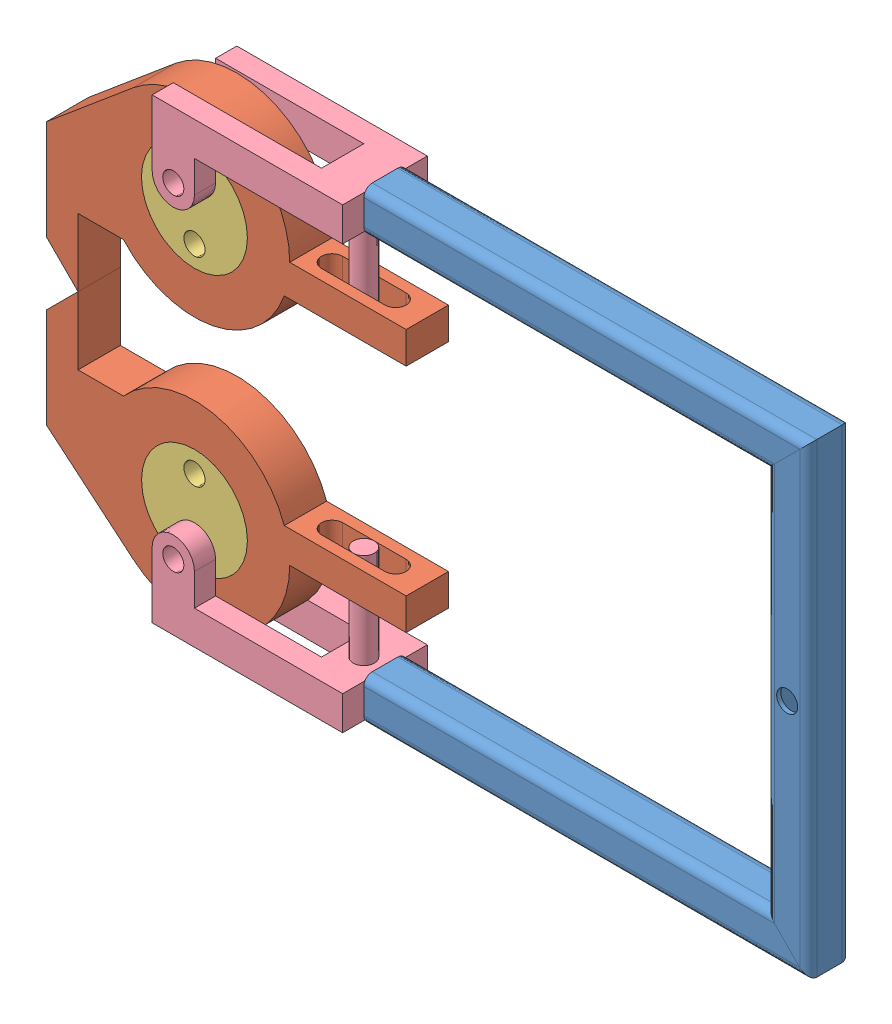
SolidWorks assembly Assem1, configuration Default. Lengths in mm.
Overall size (360 220 40).
7 component instances, 4 part files, 18 mates.
Components (placement in the parent):
- Part1-1: Part1 [Default<As Machined>] at (95.7224 77.7115 186.8939) size (210 220 20)
- Part2-1: Part2 [Default] at (15.7224 115.7115 176.8939) size (170 107 20)
- Part3-1: Part3 [Default] at (15.7224 115.7115 176.8939) x (-1 0 0) z (0 0 1) size (50 50 20)
- Part3-2: Part3 [Default] at (15.7224 239.7115 176.8939) x (1 0 0) z (0 0 1) size (50 50 20)
- Part4-1: Part4 [Default] at (5.7224 69.7115 206.8939) size (120 61 40)
- Part4-2: Part4 [Default] at (5.7224 285.7115 166.8939) x (1 0 0) z (0 0 -1) size (120 61 40)
- Part2-3: Part2 [Default] at (15.7224 239.7115 196.8939) x (1 0 0) z (0 0 -1) size (170 107 20)
Mates (geometry in assembly coordinates):
- Coincident1: coincident: plane of Part1-1 through (295.7224 83.7115 194.8939) normal (0 0 -1); plane of Part4-1 through (95.7224 85.7115 194.8939) normal (0 0 1)
- Coincident2: coincident: plane of Part1-1 through (295.7224 85.7115 192.8939) normal (0 -1 0); plane of Part4-1 through (5.7224 85.7115 206.8939) normal (0 1 0)
- Coincident3: coincident: plane of Part1-1 through (95.7224 269.7115 192.8939) normal (0 1 0); plane of Part4-2 through (5.7224 269.7115 166.8939) normal (0 -1 0)
- Coincident4: coincident: plane of Part1-1 through (95.7224 271.7115 194.8939) normal (0 0 -1); plane of Part4-2 through (95.7224 269.7115 194.8939) normal (0 0 1)
- Concentric1: concentric: cylinder of Part2-1 through (15.7224 115.7115 196.8939) axis (0 0 -1) radius 25; cylinder of Part3-1 through (15.7224 115.7115 196.8939) axis (0 0 -1) radius 25; cylinder of Part3-1 through (15.7224 115.7115 196.8939) axis (0 0 -1) radius 25
- Coincident6: coincident: plane of Part2-1 through (15.7224 115.7115 196.8939) normal (0 0 1); plane of Part3-1 through (15.7224 115.7115 196.8939) normal (0 0 1)
- Concentric3: concentric: cylinder of Part3-2 through (15.7224 254.7115 196.8939) axis (0 0 -1) radius 5; cylinder of Part4-2 through (15.7224 254.7115 206.8939) axis (0 0 -1) radius 5
- Concentric4: concentric: cylinder of Part3-1 through (15.7224 100.7115 196.8939) axis (0 0 -1) radius 5; cylinder of Part4-1 through (15.7224 100.7115 196.8939) axis (0 0 1) radius 5
- Coincident7: coincident: plane of Part3-2 through (15.6758 239.7116 196.8939) normal (0 0 1); plane of Part2-3 through (15.6758 239.7116 196.8939) normal (0 0 1)
- Concentric5: concentric: cylinder of Part3-2 through (15.6758 239.7116 196.8939) axis (0 0 -1) radius 25; cylinder of Part2-3 through (15.6758 239.7116 176.8939) axis (0 0 1) radius 25; cylinder of Part2-3 through (15.6758 239.7116 176.8939) axis (0 0 1) radius 25
- Coincident9: coincident: plane of Part2-1 through (15.7224 115.7115 176.8939) normal (0 0 -1); plane of Part4-1 through (5.7224 85.7115 176.8939) normal (0 0 1)
- Coincident10: coincident: plane of Part4-2 through (5.7224 269.7115 176.8939) normal (0 0 1); plane of Part2-3 through (15.6758 239.7116 176.8939) normal (0 0 -1)
- Coincident11: coincident: plane of Part1-1 through (95.7224 271.7115 192.8939) normal (-1 0 0); plane of Part4-2 through (95.7224 269.7115 194.8939) normal (1 0 0)
- Coincident12: coincident: plane of Part1-1 through (95.7224 83.7115 192.8939) normal (-1 0 0); plane of Part4-1 through (95.7224 85.7115 206.8939) normal (1 0 0)
- Parallel4: parallel: line of Part4-2 through (95.7224 269.7115 206.8939) axis (0 1 0); line of Part2-3 through (115.6758 239.7116 196.8939) axis (0 -1 0)
- Parallel5: parallel: plane of Part2-1 through (115.7224 130.7115 196.8939) normal (1 0 0); plane of Part4-1 through (95.7224 85.7115 206.8939) normal (1 0 0)
- Parallel6: parallel: plane of Part4-2 through (95.7224 269.7115 194.8939) normal (1 0 0); plane of Part2-3 through (115.6758 224.7116 176.8939) normal (1 0 0)
- Initial: coincident: point of Part2-1; point of Part2-3
